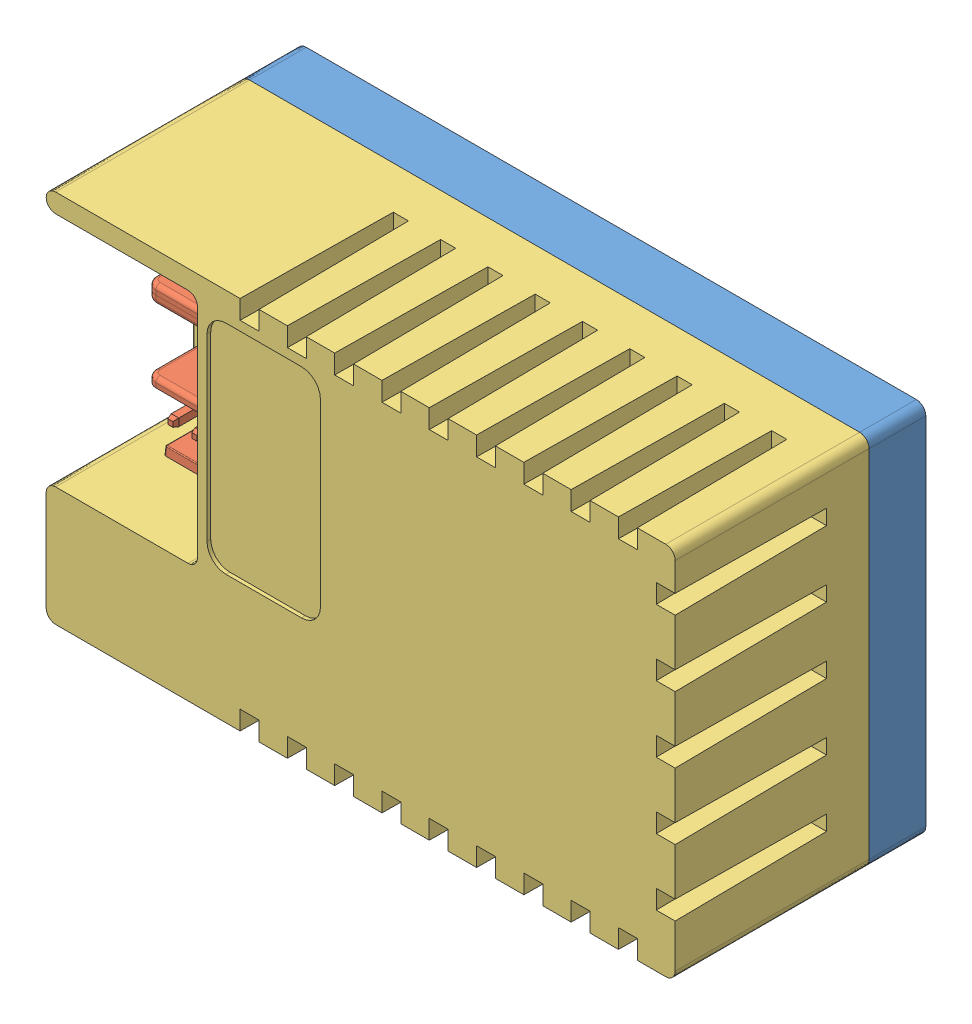
SolidWorks assembly case, configuration Default. Lengths in mm.
Overall size (66.5 39.6 26.5).
3 component instances, 3 part files, 6 mates.
Components (placement in the parent):
- base cover-1: base cover [Default] at (-3.5197 18.3603 41.9429) size (66.5 39.6 8.2)
- board_asemb-1: board_asemb [Default] at (58.4158 65.4239 3.2956) x (-1 0 0) z (0 0 1) size (61.5 34.6 20.85)
- top cover-1: top cover [Default] at (-6.0197 55.4603 68.4429) x (1 0 0) z (0 0 -1) size (66.5 39.6 20.5)
Mates (geometry in assembly coordinates):
- Coincident1: coincident anti-aligned: plane of base cover-1 through (-0.0197 24.4603 46.9429) normal (0 0 1); plane of board_asemb-1 through (57.9803 52.9603 46.9429) normal (0 0 -1)
- Concentric1: concentric aligned: cylinder of base cover-1 through (55.9803 33.4603 46.9429) axis (0 0 -1) radius 2.5; cylinder of board_asemb-1 through (55.9803 33.4603 48.5429) axis (0 0 -1) radius 1
- Concentric2: concentric anti-aligned: cylinder of base cover-1 through (-0.0197 24.4603 44.9429) axis (0 0 1) radius 0.75; cylinder of board_asemb-1 through (-0.0197 24.4603 48.5429) axis (0 0 -1) radius 1
- Coincident3: coincident aligned: plane of base cover-1 through (-6.0197 15.8603 43.9429) normal (-1 0 0); plane of top cover-1 through (-6.0197 55.4603 66.4429) normal (-1 0 0)
- Coincident4: coincident aligned: plane of base cover-1 through (-6.0197 55.4603 43.9429) normal (0 1 0); plane of top cover-1 through (-6.0197 55.4603 66.4429) normal (0 1 0)
- Coincident5: coincident anti-aligned: plane of base cover-1 through (-3.5197 18.3603 47.9429) normal (0 0 1); plane of top cover-1 through (-6.0197 55.4603 47.9429) normal (0 0 -1)
